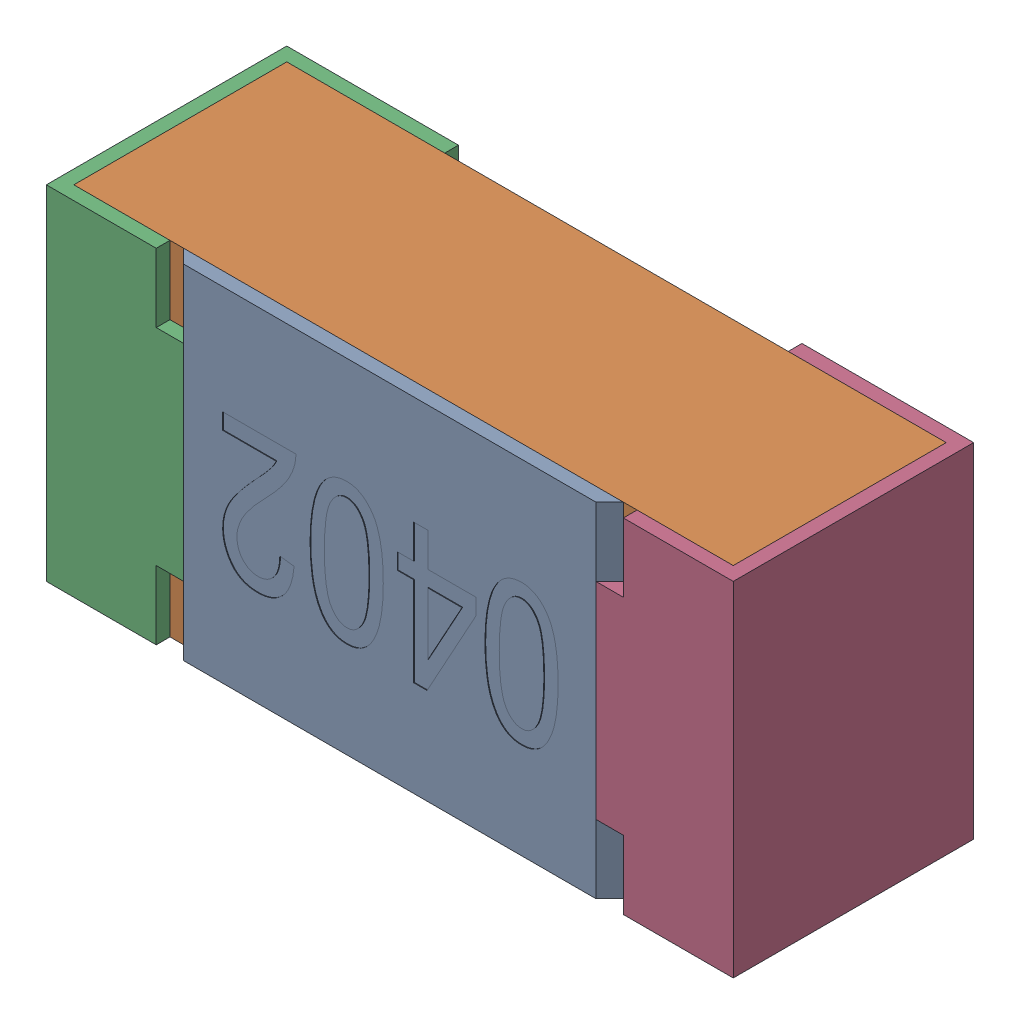
SolidWorks assembly R11, configuration Standard. Lengths in mm.
Overall size (1 0.5 0.35).
5 component instances, 4 part files, 0 mates.
Components (placement in the parent):
- R11-subassembly-1-1: R11-subassembly-1 [Standard] at (3.0999 -4.1 0) x (-1 0 0) z (0 0 1) size (1 0.5 0.35)
  - User Library-R_0402-1: User Library-R_0402 [Standard] at origin size (0.64 0.5 0.02)
  - User Library-R_0402-1-1: User Library-R_0402-1 [Standard] at origin size (0.96 0.5 0.31)
  - User Library-R_0402-2-1: User Library-R_0402-2 [Standard] at origin size (0.25 0.5 0.35)
  - User Library-R_0402-3-1: User Library-R_0402-3 [Standard] at origin size (0.25 0.5 0.35)
